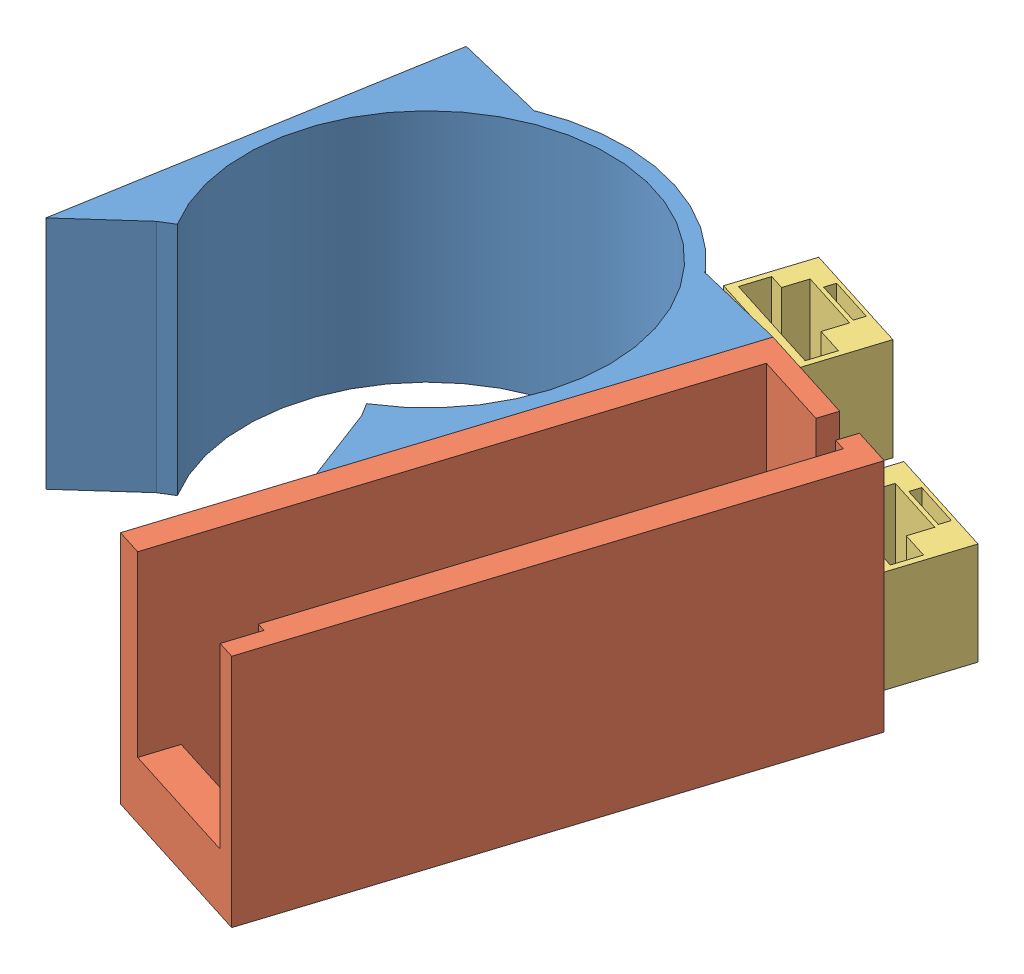
SolidWorks assembly shoe model 6, configuration Default. Lengths in mm.
Overall size (209.18 62 210.74).
4 component instances, 3 part files, 7 mates.
Components (placement in the parent):
- cycle-3: cycle [Default] at (156.2451 -8.6725 -51.3663) x (0.854007 0 -0.520262) z (0.520262 0 0.854007) size (140.87 62 140.87)
- pi_holderSLDPRT-4: pi_holderSLDPRT [Default] at (221.1294 -8.6725 65.1273) x (0.301629 0 -0.953425) z (0.953425 0 0.301629) size (137.14 62 45)
- camera holder 2.0-2: camera holder 2.0 [Default] at (239.4142 0.4403 -93.9073) x (-0.301629 0 0.953425) z (-0.953425 0 -0.301629) size (20 27 30)
- camera holder 2.0-3: camera holder 2.0 [Default] at (206.562 25.5005 -104.3005) x (-0.301629 0 0.953425) z (-0.953425 0 -0.301629) size (20 27 30)
Mates (geometry in assembly coordinates):
- Coincident26: coincident anti-aligned: plane of cycle-3 through (190.6351 53.3275 12.3273) normal (0.953425 0 0.301629); plane of pi_holderSLDPRT-4 through (178.2252 53.3275 51.554) normal (-0.953425 0 -0.301629)
- Coincident27: coincident aligned: plane of cycle-3 through (156.2451 -8.6725 -51.3663) normal (0 -1 0); plane of pi_holderSLDPRT-4 through (221.1294 -8.6725 65.1273) normal (0 -1 0)
- Coincident28: coincident aligned: line of cycle-3 through (219.5914 53.3275 -79.2015) axis (0 -1 0); line of pi_holderSLDPRT-4 through (219.5914 53.3275 -79.2015) axis (0 -1 0)
- Coincident30: coincident anti-aligned: plane of pi_holderSLDPRT-4 through (262.4956 53.3275 -65.6282) normal (0.301629 0 -0.953425); plane of camera holder 2.0-2 through (233.3817 0.4403 -74.8388) normal (-0.301629 0 0.953425)
- Parallel2: parallel aligned: plane of pi_holderSLDPRT-4 through (221.1294 -8.6725 65.1273) normal (0 -1 0); plane of camera holder 2.0-2 through (233.3817 0.4403 -74.8388) normal (0 -1 0)
- Coincident32: coincident anti-aligned: plane of pi_holderSLDPRT-4 through (262.4956 53.3275 -65.6282) normal (0.301629 0 -0.953425); plane of camera holder 2.0-3 through (200.5295 25.5005 -85.232) normal (-0.301629 0 0.953425)
- Parallel4: parallel aligned: plane of pi_holderSLDPRT-4 through (221.1294 -8.6725 65.1273) normal (0 -1 0); plane of camera holder 2.0-3 through (200.5295 25.5005 -85.232) normal (0 -1 0)
